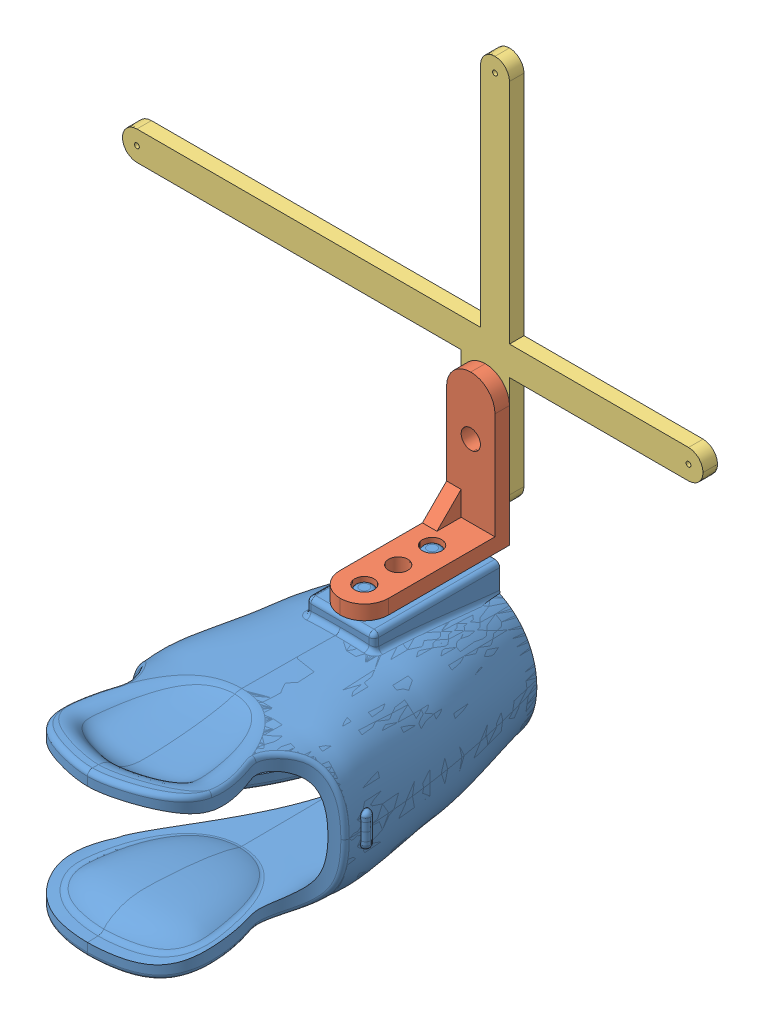
SolidWorks assembly Telemed-OldC5-Concept, configuration Default. Lengths in mm.
Overall size (120 122.89 86.63).
3 component instances, 3 part files, 6 mates.
Components (placement in the parent):
- Telemed-OldC5-Clip-1: Telemed-OldC5-Clip [Default] at (35.0803 56.0453 53.6952) size (49.36 39.39 83.08)
- ArmL-30-1: ArmL-30 [Default] at (27.4803 66.5453 25.3717) x (0 -1 0) z (0 0 1) size (30 10 32.5)
- PolarisMarker1-1: PolarisMarker1 [Default] at (37.4803 72.5453 25.3717) x (-1 0 0) z (0 -1 0) size (120 3 80)
Mates (geometry in assembly coordinates):
- Coincident1: coincident anti-aligned: plane of Telemed-OldC5-Clip-1 through (35.0803 66.5453 53.6952) normal (0 1 0); plane of ArmL-30-1 through (37.4803 66.5453 55.3717) normal (0 -1 0)
- Concentric1: concentric anti-aligned: circle of Telemed-OldC5-Clip-1; circle of ArmL-30-1
- Coincident3: coincident anti-aligned: plane of ArmL-30-1 through (37.4803 66.5453 25.3717) normal (0 0 -1); plane of PolarisMarker1-1 through (37.4803 72.5453 25.3717) normal (0 0 1)
- Concentric3: concentric aligned: circle of ArmL-30-1; circle of PolarisMarker1-1
- Concentric4: concentric anti-aligned: circle of ArmL-30-1; circle of PolarisMarker1-1
- Concentric5: concentric anti-aligned: circle of Telemed-OldC5-Clip-1; circle of ArmL-30-1
